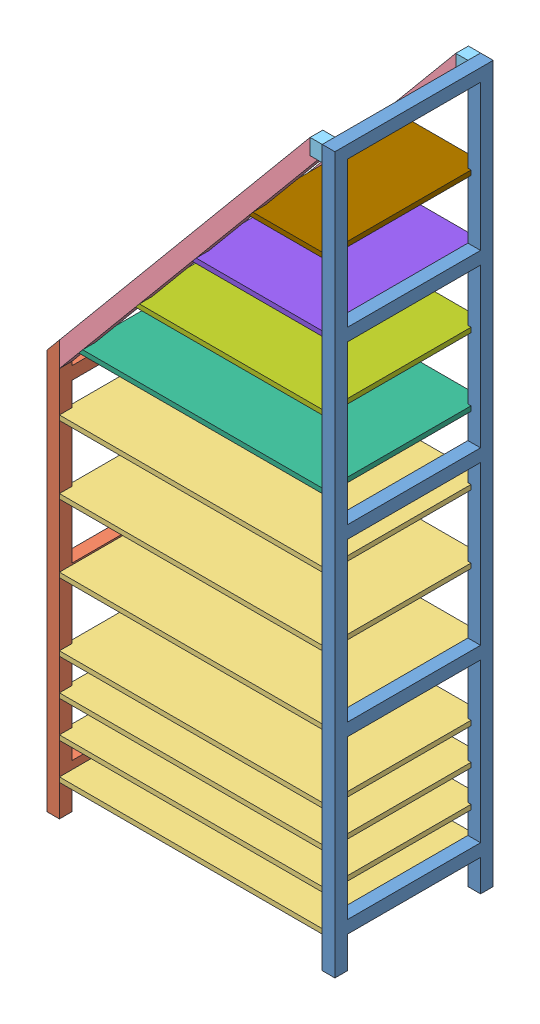
SolidWorks assembly Arbeitsregal, configuration Standard. Lengths in mm.
Overall size (910 2260 500).
17 component instances, 9 part files, 48 mates.
Components (placement in the parent):
- Seite-50-226-1: Seite-50-226 [Standard] at (844.5103 142.2315 2596.397) size (40 2260 500)
- Seite-50-226-Cut-1: Seite-50-226-Cut [Standard] at (-25.4897 142.2315 2596.397) size (40 1310.13 500)
- Boden-50-83-1: Boden-50-83 [Standard] at (429.5103 -887.7685 2596.397) size (850 15 500)
- Boden-50-83-2: Boden-50-83 [Standard] at (429.5103 -772.7685 2596.397) size (850 15 500)
- Boden-50-83-3: Boden-50-83 [Standard] at (429.5103 -657.7685 2596.397) size (850 15 500)
- Boden-50-83-4: Boden-50-83 [Standard] at (429.5103 -542.7685 2596.397) size (850 15 500)
- Boden-50-83-5: Boden-50-83 [Standard] at (429.5103 -327.7685 2596.397) size (850 15 500)
- Boden-50-83-6: Boden-50-83 [Standard] at (429.5103 -112.7685 2596.397) size (850 15 500)
- Boden-50-83-7: Boden-50-83 [Standard] at (429.5103 102.2315 2596.397) size (850 15 500)
- Schrägbalken-1: Schrägbalken [Standard] at (91.1911 232.5734 2806.397) size (815.07 1027.97 40)
- Querbalken-1: Querbalken [Standard] at (837.0496 1247.2315 2806.397) size (38.34 50 40)
- Boden-50-83-1-1: Boden-50-83-1 [Standard] at (429.5103 317.2315 2596.397) size (850 15 500)
- Boden-50-83-2-1: Boden-50-83-2 [Standard] at (429.5103 532.2315 2596.397) size (850 15 500)
- Boden-50-83-3-1: Boden-50-83-3 [Standard] at (429.5103 747.2315 2596.397) size (850 15 500)
- Boden-50-83-4-1: Boden-50-83-4 [Standard] at (429.5103 962.2315 2596.397) size (850 15 500)
- Querbalken-2: Querbalken [Standard] at (837.0496 1247.2315 2346.397) size (38.34 50 40)
- Schrägbalken-2: Schrägbalken [Standard] at (91.1911 232.5734 2346.397) size (815.07 1027.97 40)
Mates (geometry in assembly coordinates):
- Deckungsgleich1: coincident aligned: plane of Seite-50-226-1 through (884.5103 1272.2315 2846.397) normal (0 0 1); plane of Boden-50-83-1 through (14.5103 -872.7685 2846.397) normal (0 0 1)
- Deckungsgleich2: coincident aligned: plane of Seite-50-226-1 through (884.5103 1272.2315 2846.397) normal (0 0 1); plane of Boden-50-83-2 through (14.5103 -757.7685 2846.397) normal (0 0 1)
- Deckungsgleich3: coincident aligned: plane of Seite-50-226-1 through (884.5103 1272.2315 2846.397) normal (0 0 1); plane of Boden-50-83-3 through (14.5103 -642.7685 2846.397) normal (0 0 1)
- Deckungsgleich4: coincident aligned: plane of Seite-50-226-1 through (884.5103 1272.2315 2846.397) normal (0 0 1); plane of Boden-50-83-4 through (14.5103 -527.7685 2846.397) normal (0 0 1)
- Deckungsgleich5: coincident aligned: plane of Seite-50-226-1 through (884.5103 1272.2315 2846.397) normal (0 0 1); plane of Boden-50-83-5 through (14.5103 -312.7685 2846.397) normal (0 0 1)
- Deckungsgleich6: coincident aligned: plane of Seite-50-226-1 through (884.5103 1272.2315 2846.397) normal (0 0 1); plane of Boden-50-83-6 through (14.5103 -97.7685 2846.397) normal (0 0 1)
- Deckungsgleich7: coincident aligned: plane of Seite-50-226-1 through (884.5103 1272.2315 2846.397) normal (0 0 1); plane of Boden-50-83-7 through (14.5103 117.2315 2846.397) normal (0 0 1)
- Deckungsgleich10: coincident anti-aligned: plane of Seite-50-226-1 through (844.5103 142.2315 2596.397) normal (-1 0 0); plane of Boden-50-83-1 through (844.5103 -872.7685 2846.397) normal (1 0 0)
- Deckungsgleich11: coincident anti-aligned: plane of Seite-50-226-1 through (844.5103 142.2315 2596.397) normal (-1 0 0); plane of Boden-50-83-2 through (844.5103 -757.7685 2846.397) normal (1 0 0)
- Deckungsgleich12: coincident anti-aligned: plane of Seite-50-226-1 through (844.5103 142.2315 2596.397) normal (-1 0 0); plane of Boden-50-83-3 through (844.5103 -642.7685 2846.397) normal (1 0 0)
- Deckungsgleich13: coincident anti-aligned: plane of Seite-50-226-1 through (844.5103 142.2315 2596.397) normal (-1 0 0); plane of Boden-50-83-4 through (844.5103 -527.7685 2846.397) normal (1 0 0)
- Deckungsgleich14: coincident anti-aligned: plane of Seite-50-226-1 through (844.5103 142.2315 2596.397) normal (-1 0 0); plane of Boden-50-83-5 through (844.5103 -312.7685 2846.397) normal (1 0 0)
- Deckungsgleich15: coincident anti-aligned: plane of Seite-50-226-1 through (844.5103 142.2315 2596.397) normal (-1 0 0); plane of Boden-50-83-6 through (844.5103 -97.7685 2846.397) normal (1 0 0)
- Deckungsgleich16: coincident anti-aligned: plane of Seite-50-226-1 through (844.5103 142.2315 2596.397) normal (-1 0 0); plane of Boden-50-83-7 through (844.5103 117.2315 2846.397) normal (1 0 0)
- Abstand1: distance = 100 mm aligned: plane of Boden-50-83-1 through (429.5103 -887.7685 2596.397) normal (0 -1 0); plane of Seite-50-226-1 through (884.5103 -987.7685 2846.397) normal (0 -1 0)
- Abstand2: distance = 100 mm anti-aligned: plane of Boden-50-83-2 through (429.5103 -772.7685 2596.397) normal (0 -1 0); plane of Boden-50-83-1 through (429.5103 -872.7685 2596.397) normal (0 1 0)
- Abstand3: distance = 100 mm anti-aligned: plane of Boden-50-83-3 through (429.5103 -657.7685 2596.397) normal (0 -1 0); plane of Boden-50-83-2 through (429.5103 -757.7685 2596.397) normal (0 1 0)
- Abstand4: distance = 100 mm anti-aligned: plane of Boden-50-83-3 through (429.5103 -642.7685 2596.397) normal (0 1 0); plane of Boden-50-83-4 through (429.5103 -542.7685 2596.397) normal (0 -1 0)
- Abstand5: distance = 200 mm anti-aligned: plane of Boden-50-83-4 through (429.5103 -527.7685 2596.397) normal (0 1 0); plane of Boden-50-83-5 through (429.5103 -327.7685 2596.397) normal (0 -1 0)
- Abstand6: distance = 200 mm anti-aligned: plane of Boden-50-83-6 through (429.5103 -112.7685 2596.397) normal (0 -1 0); plane of Boden-50-83-5 through (429.5103 -312.7685 2596.397) normal (0 1 0)
- Abstand7: distance = 200 mm anti-aligned: plane of Boden-50-83-6 through (429.5103 -97.7685 2596.397) normal (0 1 0); plane of Boden-50-83-7 through (429.5103 102.2315 2596.397) normal (0 -1 0)
- Deckungsgleich41: coincident aligned: plane of Seite-50-226-Cut-1 through (14.5103 1272.2315 2846.397) normal (0 0 1); plane of Boden-50-83-1 through (14.5103 -872.7685 2846.397) normal (0 0 1)
- Deckungsgleich42: coincident aligned: plane of Seite-50-226-1 through (884.5103 -987.7685 2846.397) normal (0 -1 0); plane of Seite-50-226-Cut-1 through (14.5103 -987.7685 2846.397) normal (0 -1 0)
- Deckungsgleich43: coincident anti-aligned: plane of Seite-50-226-Cut-1 through (14.5103 142.2315 2596.397) normal (1 0 0); plane of Boden-50-83-1 through (14.5103 -872.7685 2806.397) normal (-1 0 0)
- Deckungsgleich44: coincident anti-aligned: plane of Seite-50-226-Cut-1 through (14.5103 142.2315 2596.397) normal (1 0 0); plane of Schrägbalken-1 through (14.5103 322.3575 2846.397) normal (-1 0 0)
- Deckungsgleich45: coincident aligned: plane of Seite-50-226-Cut-1 through (14.5103 1272.2315 2846.397) normal (0 0 1); plane of Schrägbalken-1 through (91.1911 232.5734 2846.397) normal (0 0 1)
- Deckungsgleich46: coincident aligned: plane of Seite-50-226-Cut-1 through (-25.4897 274.3633 2346.397) normal (-0.768183 0.64023 0); plane of Schrägbalken-1 through (806.1675 1272.2315 2846.397) normal (-0.768183 0.64023 0)
- Deckungsgleich47: coincident aligned: plane of Seite-50-226-1 through (884.5103 1272.2315 2846.397) normal (0 0 1); plane of Querbalken-1 through (837.0496 1247.2315 2846.397) normal (0 0 1)
- Deckungsgleich48: coincident anti-aligned: plane of Seite-50-226-1 through (844.5103 142.2315 2596.397) normal (-1 0 0); plane of Querbalken-1 through (844.5103 1222.2315 2846.397) normal (1 0 0)
- Deckungsgleich49: coincident anti-aligned: plane of Schrägbalken-1 through (829.5845 1222.2315 2846.397) normal (0 1 0); plane of Querbalken-1 through (806.1675 1222.2315 2846.397) normal (0 -1 0)
- Deckungsgleich50: coincident aligned: plane of Seite-50-226-1 through (884.5103 1272.2315 2846.397) normal (0 0 1); plane of Boden-50-83-1-1 through (14.5103 332.2315 2846.397) normal (0 0 1)
- Deckungsgleich51: coincident anti-aligned: plane of Seite-50-226-1 through (844.5103 142.2315 2596.397) normal (-1 0 0); plane of Boden-50-83-1-1 through (844.5103 332.2315 2846.397) normal (1 0 0)
- Abstand14: distance = 200 mm anti-aligned: plane of Boden-50-83-1-1 through (429.5103 317.2315 2596.397) normal (0 -1 0); plane of Boden-50-83-7 through (429.5103 117.2315 2596.397) normal (0 1 0)
- Deckungsgleich53: coincident anti-aligned: plane of Seite-50-226-1 through (844.5103 142.2315 2596.397) normal (-1 0 0); plane of Boden-50-83-2-1 through (844.5103 547.2315 2846.397) normal (1 0 0)
- Deckungsgleich54: coincident aligned: plane of Seite-50-226-1 through (884.5103 1272.2315 2846.397) normal (0 0 1); plane of Boden-50-83-2-1 through (14.5103 547.2315 2846.397) normal (0 0 1)
- Abstand15: distance = 200 mm anti-aligned: plane of Boden-50-83-1-1 through (429.5103 332.2315 2596.397) normal (0 1 0); plane of Boden-50-83-2-1 through (429.5103 532.2315 2596.397) normal (0 -1 0)
- Deckungsgleich56: coincident aligned: plane of Seite-50-226-1 through (884.5103 1272.2315 2846.397) normal (0 0 1); plane of Boden-50-83-3-1 through (14.5103 762.2315 2846.397) normal (0 0 1)
- Deckungsgleich57: coincident anti-aligned: plane of Seite-50-226-1 through (844.5103 142.2315 2596.397) normal (-1 0 0); plane of Boden-50-83-3-1 through (844.5103 762.2315 2846.397) normal (1 0 0)
- Abstand16: distance = 200 mm anti-aligned: plane of Boden-50-83-2-1 through (429.5103 547.2315 2596.397) normal (0 1 0); plane of Boden-50-83-3-1 through (429.5103 747.2315 2596.397) normal (0 -1 0)
- Deckungsgleich59: coincident anti-aligned: plane of Seite-50-226-1 through (844.5103 142.2315 2596.397) normal (-1 0 0); plane of Boden-50-83-4-1 through (844.5103 977.2315 2846.397) normal (1 0 0)
- Deckungsgleich60: coincident aligned: plane of Seite-50-226-1 through (884.5103 1272.2315 2846.397) normal (0 0 1); plane of Boden-50-83-4-1 through (14.5103 977.2315 2846.397) normal (0 0 1)
- Abstand17: distance = 200 mm anti-aligned: plane of Boden-50-83-3-1 through (429.5103 762.2315 2596.397) normal (0 1 0); plane of Boden-50-83-4-1 through (429.5103 962.2315 2596.397) normal (0 -1 0)
- Deckungsgleich62: coincident aligned: plane of Seite-50-226-1 through (884.5103 1272.2315 2346.397) normal (0 0 -1); plane of Querbalken-2 through (837.0496 1247.2315 2346.397) normal (0 0 -1)
- Deckungsgleich63: coincident aligned: plane of Querbalken-2 through (837.0496 1247.2315 2346.397) normal (0 0 -1); plane of Schrägbalken-2 through (91.1911 232.5734 2346.397) normal (0 0 -1)
- Deckungsgleich64: coincident anti-aligned: plane of Querbalken-2 through (806.1675 1222.2315 2386.397) normal (-1 0 0); plane of Schrägbalken-2 through (806.1675 1222.2315 2386.397) normal (1 0 0)
- Deckungsgleich65: coincident anti-aligned: plane of Querbalken-2 through (806.1675 1222.2315 2386.397) normal (0 -1 0); plane of Schrägbalken-2 through (829.5845 1222.2315 2386.397) normal (0 1 0)
- Deckungsgleich67: coincident anti-aligned: plane of Seite-50-226-1 through (844.5103 142.2315 2596.397) normal (-1 0 0); plane of Querbalken-2 through (844.5103 1222.2315 2386.397) normal (1 0 0)
- Deckungsgleich68: coincident aligned: plane of Seite-50-226-Cut-1 through (-25.4897 274.3633 2346.397) normal (-0.768183 0.64023 0); plane of Schrägbalken-2 through (806.1675 1272.2315 2386.397) normal (-0.768183 0.64023 0)
